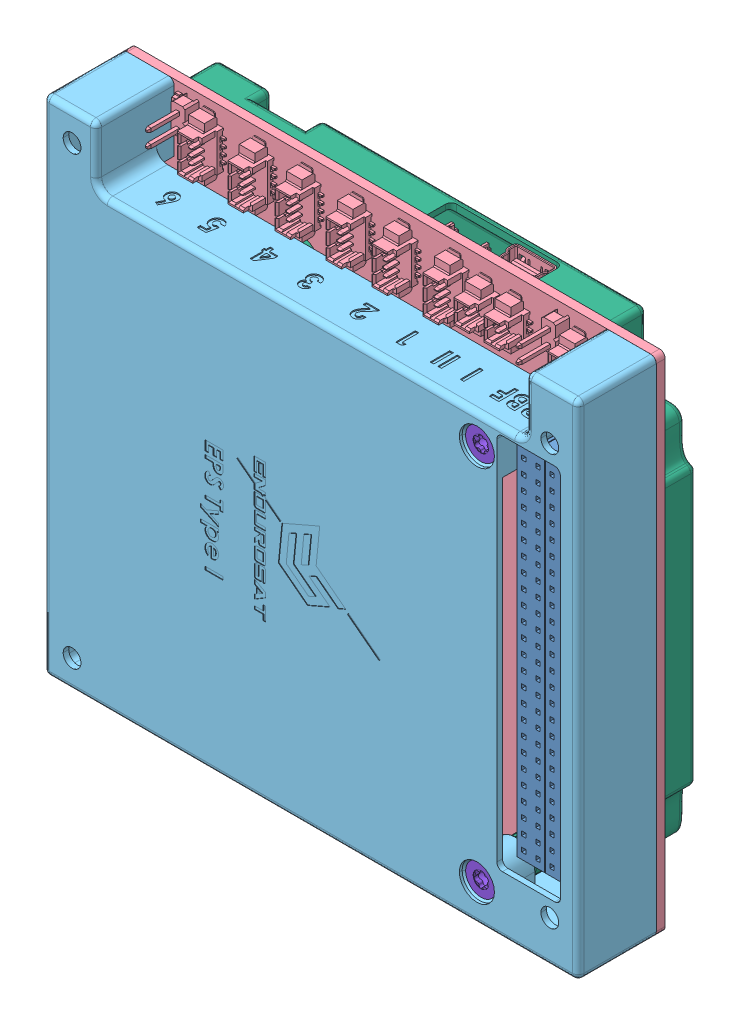
SolidWorks assembly EPS1 - Battery, configuration Default. Lengths in mm.
Overall size (95.9 90.21 21.2).
16 component instances, 8 part files, 0 mates.
Components (placement in the parent):
- EPS1 - Battery.STEP-1: EPS1 - Battery.STEP [Default] at origin size (95.9 90.21 21.2)
  - ESQ_126_37_G_D.STEP-1: ESQ_126_37_G_D.STEP [Default] at (61.557 47.1532 82.7332) x (0 1 0) z (1 0 0) size (66.55 13.33 5.08)
    - _ESQ_126_37_G_D_socket_2.STEP-1: _ESQ_126_37_G_D_socket_2.STEP [Default] at (-33.274 0 0) size (66.55 8.51 4.95)
    - _ESQ_126_37_G_D_pins_4.STEP-1: _ESQ_126_37_G_D_pins_4.STEP [Default] at origin size (65.79 9.77 4.7)
    - _ESQ_126_37_G_D_LL_bpins_6.STEP-1: _ESQ_126_37_G_D_LL_bpins_6.STEP [Default] at (-33.147 -2.54 0) size (66.04 2.54 5.08)
  - ESQ_126_37_G_D.STEP-2: ESQ_126_37_G_D.STEP [Default] at (66.637 47.1532 82.7332) x (0 1 0) z (1 0 0) size (66.55 13.33 5.08)
    - _ESQ_126_37_G_D_socket_2.STEP-1: _ESQ_126_37_G_D_socket_2.STEP [Default] at (-33.274 0 0) size (66.55 8.51 4.95)
    - _ESQ_126_37_G_D_pins_4.STEP-1: _ESQ_126_37_G_D_pins_4.STEP [Default] at origin size (65.79 9.77 4.7)
    - _ESQ_126_37_G_D_LL_bpins_6.STEP-1: _ESQ_126_37_G_D_LL_bpins_6.STEP [Default] at (-33.147 -2.54 0) size (66.04 2.54 5.08)
  - ES_EPS_Rev1_4_PCB_STEP.STEP-1: ES_EPS_Rev1_4_PCB_STEP.STEP [Default] at (-22.8876 2.7023 80.1932) size (95.9 90.21 13.97)
  - top-cover_EPS1.STEP-1: top-cover_EPS1.STEP [Default] at (-22.8876 2.7023 80.1932) size (95.9 90.2 14)
  - bottom-cover_Rev1.2.STEP-1: bottom-cover_Rev1.2.STEP [Default] at (25.0624 47.8023 72.9932) size (95.9 90.2 13.5)
  - TR Fastenings Ltd-M2_5X4mm.STEP-1: TR Fastenings Ltd-M2_5X4mm.STEP [Default] at (-22.8876 68.8523 83.4832) x (0 0.841973 -0.539519) z (-1 0 0) size (4.7 4.7 4)
  - TR Fastenings Ltd-M2_5X4mm.STEP-2: TR Fastenings Ltd-M2_5X4mm.STEP [Default] at (-22.8876 26.7523 83.4832) x (0 0.924225 0.381849) z (-1 0 0) size (4.7 4.7 4)
  - 965 M3x6 Torx_M3X6mm.STEP-1: 965 M3x6 Torx_M3X6mm.STEP [Default] at (54.8324 9.3023 93.4576) x (0.993054 -0.117656 0) z (0 0 1) size (5.5 5.5 6)
  - 965 M3x6 Torx_M3X6mm.STEP-2: 965 M3x6 Torx_M3X6mm.STEP [Default] at (54.8324 77.0023 93.4697) x (0.987647 0.156698 0) z (0 0 1) size (5.5 5.5 6)
